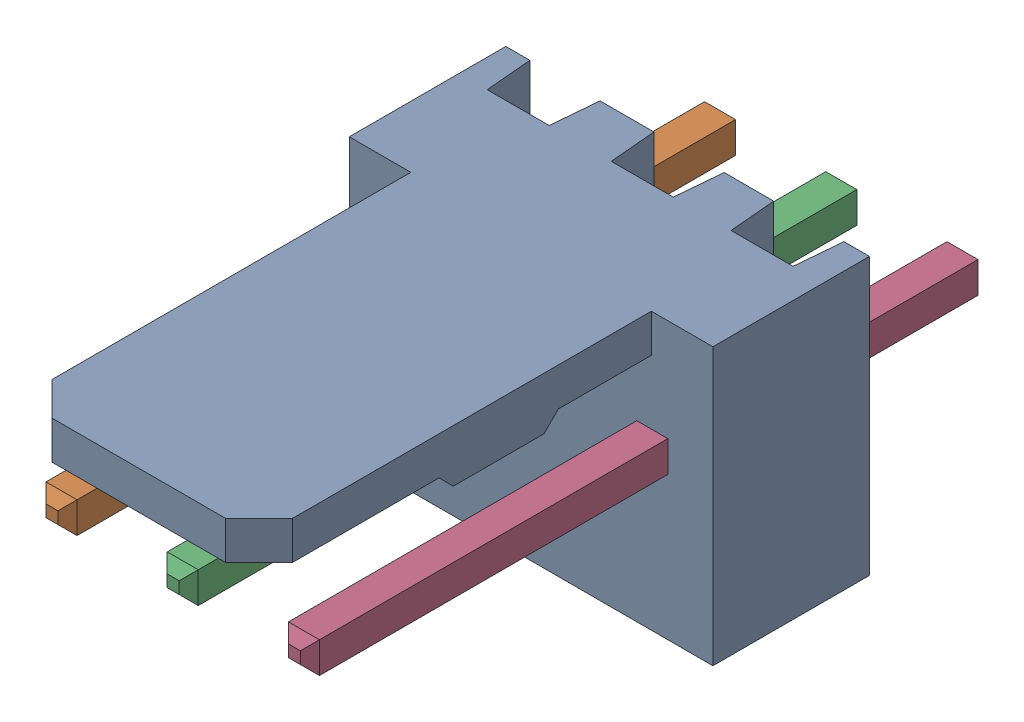
SolidWorks assembly Molex PCB 3 pin v2 v6_3, configuration Default. Lengths in mm.
Overall size (7.62 5.79 14.92).
4 component instances, 2 part files, 0 mates.
Components (placement in the parent):
- BASE9710016 (1)-1: BASE9710016 (1) [Default] at (2.54 2.895 -8.22) size (7.62 5.79 11.5)
- PINO9710016 (1)-1: PINO9710016 (1) [Default] at (1.27 3.325 -0.72) size (0.65 0.65 14.2)
- PINO9710016 (1)-2: PINO9710016 (1) [Default] at (3.81 3.325 -0.72) size (0.65 0.65 14.2)
- PINO9710016 (1)-3: PINO9710016 (1) [Default] at (6.35 3.325 -0.72) size (0.65 0.65 14.2)
